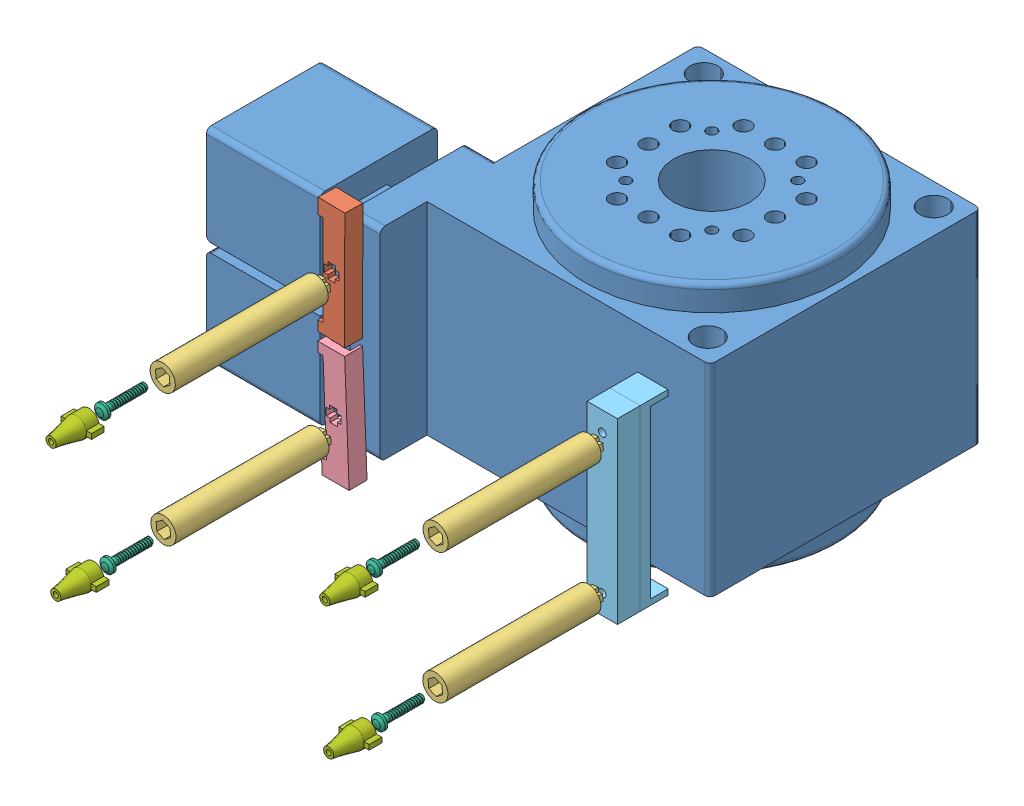
SolidWorks assembly 装配体1, configuration 默认. Lengths in mm.
Overall size (188.65 100.76 249.19).
16 component instances, 7 part files, 0 mates.
Components (placement in the parent):
- 零件_转台模型-1: 零件_转台模型 [默认] at (-2.0045 -44.0944 171.491) size (180.71 100 125.72)
- bottom_circlemotor-1: bottom_circlemotor [默认] at (-75.2158 0.666 255.829) x (-0.999766 0.000533 -0.021643) z (-0.000582 -0.999997 0.002269) size (10.8 7 46.21)
- bottom_foot_tip_counter-1: bottom_foot_tip_counter [默认] at (-67.3376 21.7741 323.3603) x (1 0 0) z (0 1 0) size (10 63.5 10)
- bottom_squaremotor-1: bottom_squaremotor [默认] at (-57.1444 -10.9757 255.7187) x (-0.017112 0.999629 0.021193) z (-0.999732 -0.016776 -0.015946) size (46 7 10.85)
- BottomPlate-1: BottomPlate [默认] at (30.4968 40.7691 247.0247) x (0 -1 0) z (1 0 0) size (70.61 20 12.13)
- 小零件_螺丝钉-1: 小零件_螺丝钉 [默认] at (-67.7806 21.7395 330.1758) x (0 0 1) z (-1 0 0) size (18.45 5.5 5.5)
- bottom_foot_tip_counter-2: bottom_foot_tip_counter [默认] at (-67.4133 -30.6719 323.017) x (1 0 0) z (0 1 0) size (10 63.5 10)
- bottom_foot_tip_counter-3: bottom_foot_tip_counter [默认] at (40.1726 -30.6904 323.0326) x (1 0 0) z (0 1 0) size (10 63.5 10)
- bottom_foot_tip_counter-4: bottom_foot_tip_counter [默认] at (40.7449 21.4202 323.4702) x (1 0 0) z (0 1 0) size (10 63.5 10)
- 小零件_螺丝钉-2: 小零件_螺丝钉 [默认] at (39.7411 21.7141 330.2024) x (0 0 1) z (-1 0 0) size (18.45 5.5 5.5)
- 小零件_螺丝钉-3: 小零件_螺丝钉 [默认] at (-67.7337 -32.1408 328.0885) x (0 0 1) z (-1 0 0) size (18.45 5.5 5.5)
- 小零件_螺丝钉-4: 小零件_螺丝钉 [默认] at (40.0117 -31.9161 328.47) x (0 0 1) z (-1 0 0) size (18.45 5.5 5.5)
- bottom_foot__tip-1: bottom_foot__tip [默认] at (-67.8369 21.2646 357.0346) x (1 0 0) z (0 -1 0) size (24.4 15 9.57)
- bottom_foot__tip-2: bottom_foot__tip [默认] at (40.3625 21.2618 356.9657) x (1 0 0) z (0 -1 0) size (24.4 15 9.57)
- bottom_foot__tip-4: bottom_foot__tip [默认] at (40.3427 -31.9292 355.3966) x (1 0 0) z (0 -1 0) size (24.4 15 9.57)
- bottom_foot__tip-5: bottom_foot__tip [默认] at (-67.7318 -31.9969 355.2671) x (1 0 0) z (0 -1 0) size (24.4 15 9.57)
